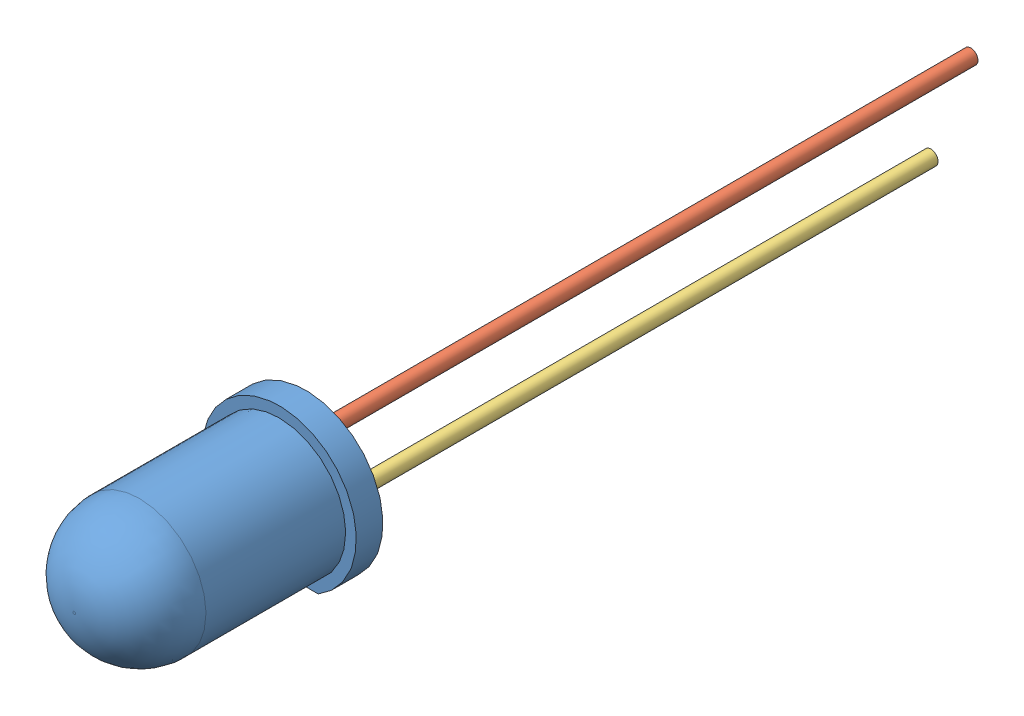
SolidWorks assembly LED 5mm white, configuration Default. Lengths in mm.
Overall size (6.76 5.4 33.7).
4 component instances, 3 part files, 0 mates.
Components (placement in the parent):
- LED 5mm white.iges-1: LED 5mm white.iges [Default] at origin size (6.76 5.4 33.7)
  - LeuchtkÃ¶rper 5mm v2.iges-1: LeuchtkÃ¶rper 5mm v2.iges [Default] at origin size (6.76 5.4 8.7)
  - Anode v2.iges-1: Anode v2.iges [Default] at (0 1.27 -25) size (0.54 0.54 25)
  - Kadode v2.iges-1: Kadode v2.iges [Default] at (0 -1.27 -25) size (0.54 0.54 23.5)
